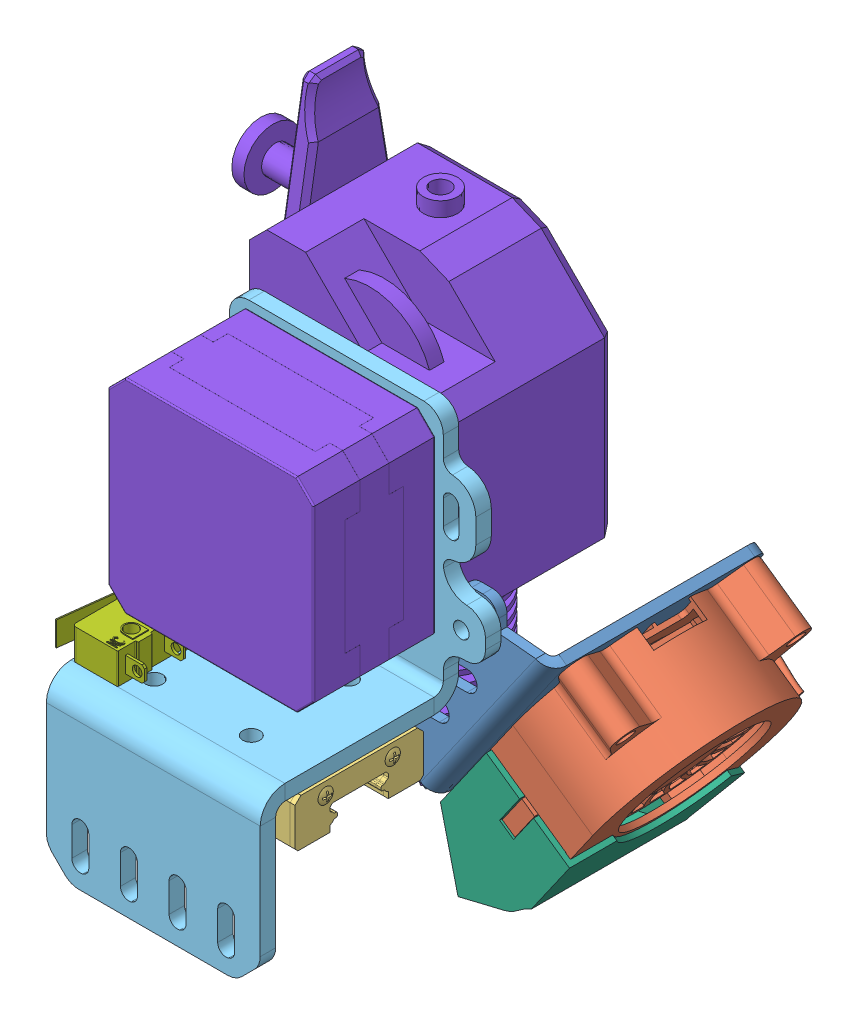
SolidWorks assembly Single Direct Drive Extruder_R3, configuration Default. Lengths in mm.
Overall size (112.74 126.39 90.61).
8 component instances, 8 part files, 25 mates.
Components (placement in the parent):
- Part Cooling Fan Mount_R3-1: Part Cooling Fan Mount_R3 [Default] at (0 28 -20.675) x (-1 0 0) z (0 -1 0) size (78.68 45.19 41.79)
- 4020Blower_R3-1: 4020Blower_R3 [Default] at (45.2772 -17.7122 -45.945) x (-0.573576 -0.819152 0) z (0 0 1) size (40.83 20 46.25)
- MGN12HZFC-HiwinCorporation-11-14-2016_R3-1: MGN12HZFC-HiwinCorporation-11-14-2016_R3 [Default] at (-22.7 -13.175 0) x (1 0 0) z (0 1 0) size (45.6 27 10)
- SN04_R3-1: SN04_R3 [Default] at (-44.175 37.8738 -130.9561) x (0 0 1) z (-1 0 0) size (18.24 34.21 18.35)
- Aluminum_Extruder_To_Carriage_Mount_R3-1: Aluminum_Extruder_To_Carriage_Mount_R3 [Default] at origin size (66 84.83 40.85)
- Part Cooling Fan V2_R3-1: Part Cooling Fan V2_R3 [Default] at (45.2772 -17.7122 -45.945) x (-0.573576 -0.819152 0) z (0.819152 -0.573576 0) size (26.71 42.37 20.9)
- Micro Switch Button_R3-1: Micro Switch Button_R3 [Default] at (-17.2 3.175 4.295) x (0 1 0) z (0 0 1) size (6.75 16.71 19.86)
- BMG-1: BMG [Default] at (15.6173 13.171 -31.5932) size (58.35 122.35 62.65)
Mates (geometry in assembly coordinates):
- Coincident13: coincident: plane of Aluminum_Extruder_To_Carriage_Mount_R3-1 through (0 0 -20.675) normal (0 0 -1); plane of Part Cooling Fan Mount_R3-1 through (0 28 -20.675) normal (0 0 1)
- Concentric16: concentric: cylinder of Aluminum_Extruder_To_Carriage_Mount_R3-1 through (25.7 12.85 -0.86) axis (0 0 -1) radius 1.6; cylinder of Part Cooling Fan Mount_R3-1 through (25.7 12.85 -22.675) axis (0 0 1) radius 1.6
- Concentric17: concentric: cylinder of Aluminum_Extruder_To_Carriage_Mount_R3-1 through (-30.3 12.85 -0.86) axis (0 0 -1) radius 1.6; cylinder of Part Cooling Fan Mount_R3-1 through (-30.3 12.85 -22.675) axis (0 0 1) radius 1.6
- Coincident15: coincident: plane of Part Cooling Fan Mount_R3-1 through (35.4761 3.1594 -20.675) normal (0.819152 -0.573576 0); plane of 4020Blower_R3-1 through (28.8941 -6.2407 -44.945) normal (-0.819152 0.573576 0)
- Concentric18: concentric: cylinder of Part Cooling Fan Mount_R3-1 through (-15.2147 45.9661 -27.4795) axis (0.819152 -0.573576 0) radius 1.75; cylinder of 4020Blower_R3-1 through (49.5609 0.6098 -27.4795) axis (-0.819152 0.573576 0) radius 1.75
- Concentric19: concentric: cylinder of Part Cooling Fan Mount_R3-1 through (-35.2503 17.3523 -62.4105) axis (0.819152 -0.573576 0) radius 1.75; cylinder of 4020Blower_R3-1 through (29.5253 -28.0041 -62.4105) axis (-0.819152 0.573576 0) radius 1.75
- Coincident26: coincident: plane of Part Cooling Fan Mount_R3-1 through (-37.55 28 -20.675) normal (-1 0 0); plane of SN04_R3-1 through (-37.55 -13.6262 -44.9561) normal (1 0 0)
- Coincident25: coincident: plane of Aluminum_Extruder_To_Carriage_Mount_R3-1 through (0 -3.175 0) normal (0 -1 0); plane of MGN12HZFC-HiwinCorporation-11-14-2016_R3-1 through (-16.2 -3.175 -6.4) normal (0 1 0)
- Concentric22: concentric: cylinder of Aluminum_Extruder_To_Carriage_Mount_R3-1 through (10 -3.175 -10) axis (0 1 0) radius 1.75; cylinder of MGN12HZFC-HiwinCorporation-11-14-2016_R3-1 through (10 -7.1125 -10) axis (0 -1 0) radius 1.2295
- Concentric23: concentric: cylinder of Aluminum_Extruder_To_Carriage_Mount_R3-1 through (-10 -3.175 -10) axis (0 1 0) radius 1.75; cylinder of MGN12HZFC-HiwinCorporation-11-14-2016_R3-1 through (-10 -7.1125 -10) axis (0 -1 0) radius 1.2295
- InPlace1: in place: plane of ? through (140.5539 -0.5372 -44.945) normal (0.819152 -0.573576 0); plane of ? through (94.5655 -66.2154 0) normal (0.819152 -0.573576 0); moOrthogonalPlaneRef_w of ? through (140.5539 -0.5372 -44.945) normal (0.819152 -0.573576 0); line of ? through (-55 94.5655 -66.2154) axis (0 0.573576 0.819152); plane of ? through (140.5539 -0.5372 -44.945) normal (0.819152 -0.573576 0); unknown of ?; plane of 4020Blower_R3-1 through (45.2772 -17.7122 -44.945) normal (0.819152 -0.573576 0); unknown of Part Cooling Fan V2_R3-1
- Coincident29: coincident: plane of 4020Blower_R3-1; plane of Part Cooling Fan V2_R3-1
- Coincident30: coincident: moOrthogonalPlaneRef_w of 4020Blower_R3-1 through (45.2772 -17.7122 -45.945) normal (0 0 -1); plane of Part Cooling Fan V2_R3-1 through (45.2772 -17.7122 -45.945) normal (0 0 -1)
- Coincident31: coincident: moOrthogonalPlaneRef_w of 4020Blower_R3-1 through (45.2772 -17.7122 -45.945) normal (0.573576 0.819152 0); plane of Part Cooling Fan V2_R3-1 through (45.2772 -17.7122 -45.945) normal (-0.573576 -0.819152 0)
- Coincident29: coincident: plane of Aluminum_Extruder_To_Carriage_Mount_R3-1 through (0 0 0) normal (0 1 0); plane of Micro Switch Button_R3-1 through (-12.6 0 -4.505) normal (0 -1 0)
- Distance1: distance = 0.5 mm: plane of Micro Switch Button_R3-1 through (-22.5 6.35 5.1122) normal (-1 0 0); plane of Aluminum_Extruder_To_Carriage_Mount_R3-1 through (-22 -3.175 17) normal (-1 0 0)
- Coincident31: coincident: plane of Aluminum_Extruder_To_Carriage_Mount_R3-1 through (0 0 0) normal (0 0 1); plane of assembly through (0 0 0) normal (0 0 1)
- Coincident32: coincident: plane of Aluminum_Extruder_To_Carriage_Mount_R3-1 through (0 0 0) normal (0 1 0); plane of assembly through (0 0 0) normal (0 1 0)
- Coincident33: coincident: plane of Aluminum_Extruder_To_Carriage_Mount_R3-1 through (0 0 0) normal (1 0 0); plane of assembly through (0 0 0) normal (1 0 0)
- Slot1: slot: cylinder of Part Cooling Fan Mount_R3-1 through (-37.55 -12.15 -41.195) axis (-1 0 0) radius 1.6; cylinder of SN04_R3-1 through (-50.8 -16.776 -41.195) axis (1 0 0) radius 1.6; cylinder of SN04_R3-1 through (-50.8 -11.476 -41.195) axis (1 0 0) radius 1.6
- Slot2: slot: cylinder of SN04_R3-1 through (-50.8 -16.776 -30.695) axis (1 0 0) radius 1.6; cylinder of Part Cooling Fan Mount_R3-1 through (-37.55 -12.15 -30.695) axis (-1 0 0) radius 1.6; cylinder of SN04_R3-1 through (-50.8 -11.476 -30.695) axis (1 0 0) radius 1.6
- Coincident34: coincident: line of Aluminum_Extruder_To_Carriage_Mount_R3-1 through (-22 0 15.095) axis (1 0 0); plane of Micro Switch Button_R3-1 through (-21 6.35 15.095) normal (0 0 1)
- Coincident35: coincident: plane of Aluminum_Extruder_To_Carriage_Mount_R3-1 through (0 0 -20.675) normal (0 0 -1); plane of BMG-1 through (0 28 -20.675) normal (0 0 1)
- Concentric24: concentric: cylinder of Aluminum_Extruder_To_Carriage_Mount_R3-1 through (15.5 43.5 20.176) axis (0 0 -1) radius 1.6; cylinder of BMG-1 through (15.5 43.5 -83.925) axis (0 0 -1) radius 1.5
- Concentric25: concentric: cylinder of Aluminum_Extruder_To_Carriage_Mount_R3-1 through (-15.5 12.5 20.176) axis (0 0 -1) radius 1.6; cylinder of BMG-1 through (-15.5 12.5 -83.925) axis (0 0 -1) radius 1.5
